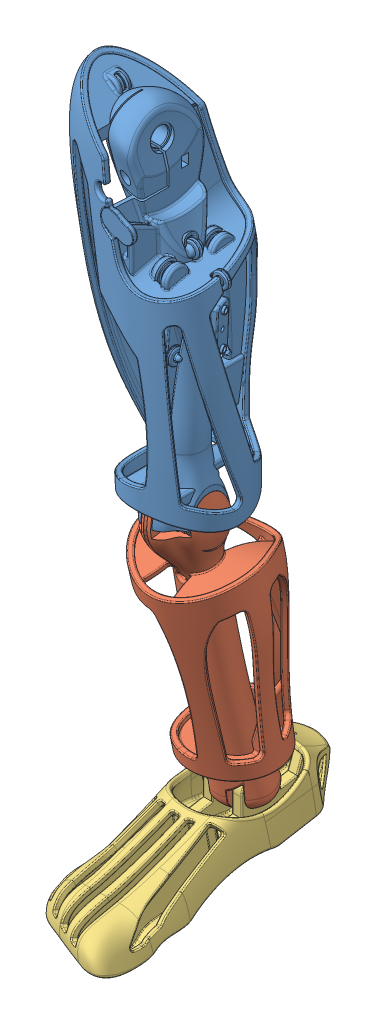
SolidWorks assembly a-bein-rechts-v02, configuration rechts. Lengths in mm.
Overall size (151.62 630.83 408.64).
5 component instances, 3 part files, 8 mates.
Components (placement in the parent):
- p-oberschenkel-v02-2: p-oberschenkel-v02 [01] at origin size (148.62 364.86 121.66)
- p-unterschenkel-v02-1: p-unterschenkel-v02 [01] at (0 -3.95 45.1485) x (1 0 0) z (0 -0.173648 0.984808) size (104.62 295.08 116.44)
- p-oberschenkel-v02-3: p-oberschenkel-v02 [01] x (-1 0 0) z (0 0 -1) size (148.62 364.86 121.66) (suppressed, hidden)
- p-unterschenkel-v02-2: p-unterschenkel-v02 [01] at (0 -3.95 45.1485) x (-1 0 0) z (0 0.173648 -0.984808) size (104.62 295.08 116.44) (suppressed, hidden)
- p-fuss-rechts-v12-1: p-fuss-rechts-v12 [rechts01] at (-11 -485.2288 -25.6419) x (-1 0 0) z (0 0.173648 -0.984808) size (88.74 74.5 238.45)
Mates (geometry in assembly coordinates):
- Deckungsgleich4: coincident anti-aligned: plane of p-oberschenkel-v02-2 through (0 0 0) normal (-1 0 0); plane of p-unterschenkel-v02-1
- Gelenk2: hinge aligned: cylinder of p-oberschenkel-v02-2 through (49.3583 -260 0) axis (-1 0 0) radius 7.9; cylinder of p-unterschenkel-v02-1 through (43.0818 -260 0) axis (-1 0 0) radius 7.1; plane of p-oberschenkel-v02-2 through (0 0 0) normal (1 0 0); plane of p-unterschenkel-v02-1
- Deckungsgleich8: coincident: point of p-oberschenkel-v02-2; point of assembly
- Deckungsgleich10: coincident aligned: plane of p-oberschenkel-v02-2 through (0 0 0) normal (0 1 0); plane of assembly through (0 0 0) normal (0 1 0)
- Knie: planar angle = 0.174533 rad anti-aligned: plane of p-unterschenkel-v02-1 through (0 -305.1485 256.05) normal (0 0.984808 0.173648); plane of p-oberschenkel-v02-2 through (0 -260 260) normal (0 -1 0)
- Konzentrisch1: concentric aligned: cylinder of p-fuss-rechts-v12-1 through (-21 -488.4754 -40.2864) axis (1 0 0) radius 6.7; cylinder of p-unterschenkel-v02-1 through (-22 -488.4754 -40.2864) axis (1 0 0) radius 7.5
- Deckungsgleich9: coincident anti-aligned: plane of p-fuss-rechts-v12-1; plane of assembly through (0 0 0) normal (1 0 0)
- Fuss: planar angle = 0 rad aligned: plane of p-fuss-rechts-v12-1; plane of p-unterschenkel-v02-1 through (0 -3.95 45.1485) normal (0 0.984808 0.173648)
